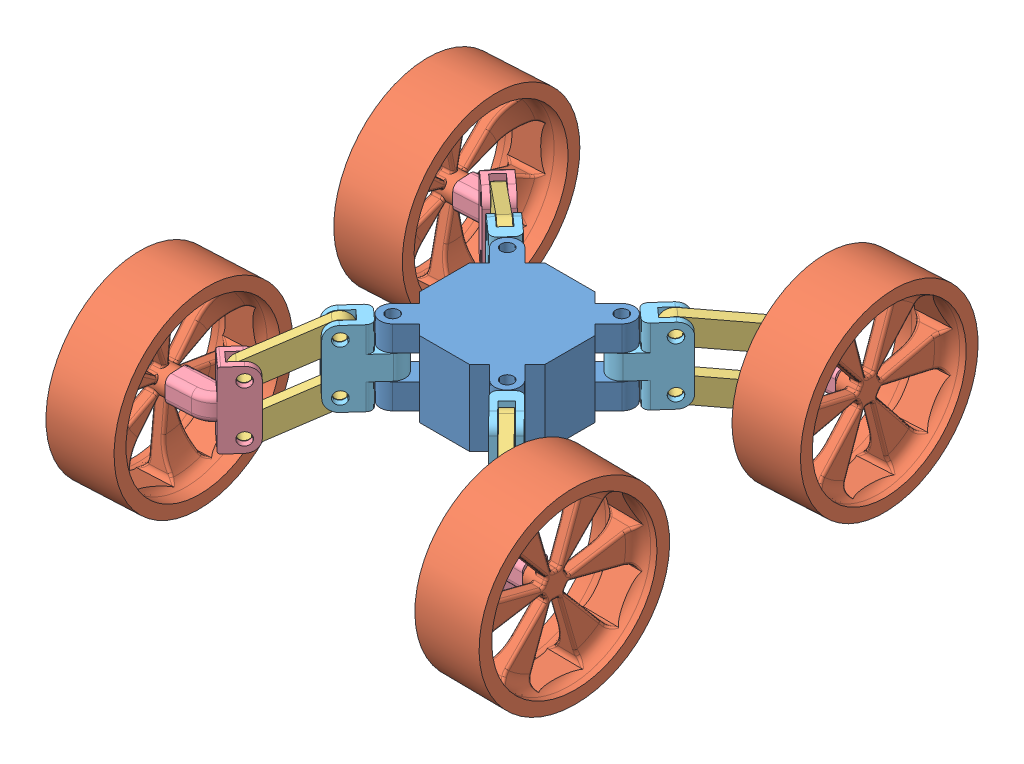
SolidWorks assembly Master Assembly, configuration Default. Lengths in mm.
Overall size (366.57 213.45 438.62).
25 component instances, 5 part files, 18 mates.
Components (placement in the parent):
- Body-1: Body [Default] at origin size (111.21 60 111.21)
- Wheel-1: Wheel [Default] at (145.1135 15.3744 123.0059) x (-0.011503 0.033891 0.999359) z (-0.999934 0 -0.011509) size (150 150 51.72)
- Leg Assembly-1: Leg Assembly [S2] at (-45.6066 30 45.6066) x (-0.670979 0 0.741477) z (-0.741477 0 -0.670979) size (202.57 79.66 34.14) (flexible)
  - Arm-1: Arm [Default] at (56.959 -33.1609 0) x (0.898635 -0.438698 0) z (0 0 1) size (80 20 9)
  - LowerJoint-1: LowerJoint [S2] at (83.9181 -26.3219 0) x (-1 0 0) z (0 0 -1) size (53.78 60 34.14)
  - UpperJoint-1: UpperJoint [Default] at origin size (50.5 60 20)
  - Arm-2: Arm [Default] at (56.959 6.8391 0) x (0.898635 -0.438698 0) z (0 0 1) size (80 20 9)
- Leg Assembly-2: Leg Assembly [S2] at (45.6066 30 -45.6066) x (0.666311 0 -0.745674) z (0.745674 0 0.666311) size (202.57 79.66 34.14) (flexible)
  - Arm-1: Arm [Default] at (59.7264 -24.0427 0) x (0.990879 -0.134756 0) z (0 0 1) size (80 20 9)
  - LowerJoint-1: LowerJoint [S2] at (89.4527 -8.0854 0) x (-1 0 0) z (0 0 -1) size (53.78 60 34.14)
  - UpperJoint-1: UpperJoint [Default] at origin size (50.5 60 20)
  - Arm-2: Arm [Default] at (59.7264 15.9573 0) x (0.990879 -0.134756 0) z (0 0 1) size (80 20 9)
- Leg Assembly-3: Leg Assembly [S1] at (-45.6066 30 -45.6066) x (-0.745674 0 -0.666311) z (0.666311 0 -0.745674) size (117.23 117.57 34.14) (flexible)
  - Arm-1: Arm [Default] at (58.6205 -28.9925 0) x (0.954018 -0.299751 0) z (0 0 1) size (80 20 9)
  - LowerJoint-1: LowerJoint [S1] at (87.2411 -17.9851 0) x (-1 0 0) z (0 0 -1) size (53.78 60 34.14)
  - UpperJoint-1: UpperJoint [Default] at origin size (50.5 60 20)
  - Arm-2: Arm [Default] at (58.6205 11.0075 0) x (0.954018 -0.299751 0) z (0 0 1) size (80 20 9)
- Leg Assembly-4: Leg Assembly [S1] at (45.6066 30 45.6066) x (0.698922 0 0.715198) z (-0.715198 0 0.698922) size (117.23 117.57 34.14) (flexible)
  - Arm-1: Arm [Default] at (59.0951 -27.3128 0) x (0.969836 -0.243759 0) z (0 0 1) size (80 20 9)
  - LowerJoint-1: LowerJoint [S1] at (88.1901 -14.6256 0) x (-1 0 0) z (0 0 -1) size (53.78 60 34.14)
  - UpperJoint-1: UpperJoint [Default] at origin size (50.5 60 20)
  - Arm-2: Arm [Default] at (59.0951 12.6872 0) x (0.969836 -0.243759 0) z (0 0 1) size (80 20 9)
- Wheel-2: Wheel [Default] at (142.4018 21.9146 -128.3106) x (0.025422 0.891501 0.452304) z (-0.998424 0 0.056118) size (150 150 51.72)
- Wheel-3: Wheel [Default] at (-149.4107 12.0149 -115.4692) x (-0.048325 -0.508373 -0.85978) z (0.998424 0 -0.056118) size (150 150 51.72)
- Wheel-4: Wheel [Default] at (-139.2054 3.6781 123.5975) x (-0.005467 -0.993968 -0.109539) z (0.998757 0 -0.049849) size (150 150 51.72)
Mates (geometry in assembly coordinates):
- Coincident1: coordinate: point of Body-1
- Concentric1: concentric aligned: cylinder of Body-1 through (45.6066 20 45.6066) axis (0 -1 0) radius 5; cylinder of Leg Assembly-4/UpperJoint-1 through (45.6066 39.5 45.6066) axis (0 -1 0) radius 5
- Width1: width anti-aligned: plane of Leg Assembly-4/UpperJoint-1 through (45.6066 39.5 45.6066) normal (0 1 0); plane of Body-1 through (45.6066 20.5 45.6066) normal (0 -1 0); plane of Leg Assembly-4/UpperJoint-1 through (0 40 0) normal (0 -1 0); plane of Body-1 through (0 20 0) normal (0 1 0)
- Coincident2: coincident anti-aligned: plane of Wheel-1 through (145.1135 15.3744 123.0059) normal (-0.999934 0 -0.011509); plane of Leg Assembly-4/LowerJoint-1 through (145.2286 25.3744 113.0066) normal (0.999934 0 0.011509)
- Concentric2: concentric anti-aligned: cylinder of Wheel-1 through (155.1128 15.3744 123.121) axis (-0.999934 0 -0.011509) radius 7.5; cylinder of Leg Assembly-4/LowerJoint-1 through (130.1145 15.3744 122.8333) axis (0.999934 0 0.011509) radius 7.5
- Concentric3: concentric aligned: cylinder of Body-1 through (-45.6066 20 45.6066) axis (0 -1 0) radius 5; cylinder of Leg Assembly-1/UpperJoint-1 through (-45.6066 39.5 45.6066) axis (0 -1 0) radius 5
- Width2: width anti-aligned: plane of Leg Assembly-1/UpperJoint-1 through (-45.6066 39.5 45.6066) normal (0 1 0); plane of Body-1 through (-45.6066 20.5 45.6066) normal (0 -1 0); plane of Leg Assembly-1/UpperJoint-1 through (0 40 0) normal (0 -1 0); plane of Body-1 through (0 20 0) normal (0 1 0)
- Concentric6: concentric aligned: cylinder of Body-1 through (-45.6066 20 -45.6066) axis (0 -1 0) radius 5; cylinder of Leg Assembly-3/UpperJoint-1 through (-45.6066 39.5 -45.6066) axis (0 -1 0) radius 5
- Concentric7: concentric aligned: cylinder of Body-1 through (45.6066 20 -45.6066) axis (0 -1 0) radius 5; cylinder of Leg Assembly-2/UpperJoint-1 through (45.6066 39.5 -45.6066) axis (0 -1 0) radius 5
- Width5: width anti-aligned: plane of Leg Assembly-2/UpperJoint-1 through (45.6066 39.5 -45.6066) normal (0 1 0); plane of Body-1 through (45.6066 20.5 -45.6066) normal (0 -1 0); plane of Leg Assembly-2/UpperJoint-1 through (0 40 0) normal (0 -1 0); plane of Body-1 through (0 20 0) normal (0 1 0)
- Width6: width anti-aligned: plane of Leg Assembly-3/UpperJoint-1 through (-45.6066 39.5 -45.6066) normal (0 1 0); plane of Body-1 through (-45.6066 20.5 -45.6066) normal (0 -1 0); plane of Leg Assembly-3/UpperJoint-1 through (0 40 0) normal (0 -1 0); plane of Body-1 through (0 20 0) normal (0 1 0)
- Concentric8: concentric anti-aligned: cylinder of Leg Assembly-1/LowerJoint-1 through (-124.2241 3.6781 122.8498) axis (-0.998757 0 0.049849) radius 7.5; cylinder of Wheel-4 through (-149.193 3.6781 124.096) axis (0.998757 0 -0.049849) radius 7.5
- Coincident4: coincident anti-aligned: plane of Leg Assembly-1/LowerJoint-1 through (-139.7039 13.6781 113.61) normal (-0.998757 0 0.049849); plane of Wheel-4 through (-139.2054 3.6781 123.5975) normal (0.998757 0 -0.049849)
- Concentric9: concentric anti-aligned: cylinder of Leg Assembly-3/LowerJoint-1 through (-134.4343 12.0149 -116.311) axis (-0.998424 0 0.056118) radius 7.5; cylinder of Wheel-3 through (-159.3949 12.0149 -114.9081) axis (0.998424 0 -0.056118) radius 7.5
- Coincident5: coincident anti-aligned: plane of Leg Assembly-3/LowerJoint-1 through (-148.8495 22.0149 -105.485) normal (-0.998424 0 0.056118); plane of Wheel-3 through (-149.4107 12.0149 -115.4692) normal (0.998424 0 -0.056118)
- Concentric10: concentric anti-aligned: cylinder of Leg Assembly-2/LowerJoint-1 through (127.4254 21.9146 -127.4688) axis (0.998424 0 -0.056118) radius 7.5; cylinder of Wheel-2 through (152.386 21.9146 -128.8718) axis (-0.998424 0 0.056118) radius 7.5
- Coincident6: coincident anti-aligned: plane of Leg Assembly-2/LowerJoint-1 through (142.963 31.9146 -118.3264) normal (0.998424 0 -0.056118); plane of Wheel-2 through (142.4018 21.9146 -128.3106) normal (-0.998424 0 0.056118)
- Parallel1: parallel anti-aligned: plane of Wheel-2 through (174.0676 21.9146 -130.0904) normal (0.998424 0 -0.056118); plane of Wheel-3 through (-181.0764 12.0149 -113.6894) normal (-0.998424 0 0.056118)
